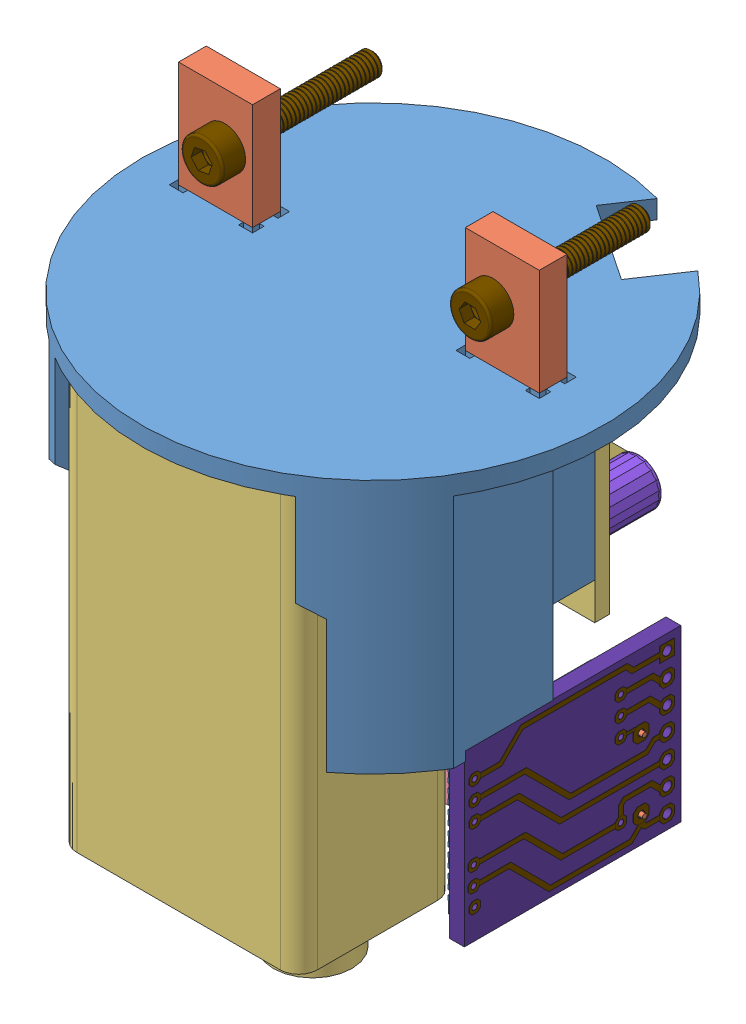
SolidWorks assembly Elektro, configuration Standard. Lengths in mm.
Overall size (50 63.5 50).
67 component instances, 62 part files, 22 mates.
Components (placement in the parent):
- E-Part-1: E-Part [Standard] at (0.3501 -2.1253 50) size (50 27.5 50)
- E-Befestigung-1: E-Befestigung [Standard] at (-12.1499 -0.1253 50.5) size (8 11.5 3)
- E-Befestigung-2: E-Befestigung [Standard] at (10.8501 -0.1253 47.5) x (-1 0 0) z (0 0 -1) size (8 11.5 3)
- 9V-1: 9V [Standard] at (-12.6499 -2.1253 54) x (0 0 -1) z (-1 0 0) size (17 50 26)
- Zeitschaltung-1: Zeitschaltung [Standard] at (0.3501 -30.1253 48.2) x (0 1 0) z (0 0 -1) size (30 30 20.34)
  - Zeitschaltung_Board-1: Zeitschaltung_Board [Standard] at origin size (30 30 1.6)
  - Zeitschaltung_PadsAndTracks-1: Zeitschaltung_PadsAndTracks [Standard] at origin size (28.67 28.55 1.67)
  - Zeitschaltung_K1-1: Zeitschaltung_K1 [Standard] at origin size (2.54 5.08 10.74) (hidden)
  - Zeitschaltung_K2-1: Zeitschaltung_K2 [Standard] at origin size (7.62 2.54 10.74) (hidden)
  - Zeitschaltung_K3-1: Zeitschaltung_K3 [Standard] at origin size (7.62 2.54 10.74) (hidden)
  - Zeitschaltung_K4-1: Zeitschaltung_K4 [Standard] at origin size (5.08 7.62 10.74)
  - Zeitschaltung_K6-1: Zeitschaltung_K6 [Standard] at origin size (2.54 5.08 10.74) (hidden)
  - Zeitschaltung_IC3-1: Zeitschaltung_IC3 [Standard] at origin size (8.8 8.8 1.61)
  - Zeitschaltung_D5-1: Zeitschaltung_D5 [Standard] at origin size (3.7 3 2.09)
  - Zeitschaltung_R1-1: Zeitschaltung_R1 [Standard] at origin size (3.2 1.6 0.61)
  - Zeitschaltung_R5-1: Zeitschaltung_R5 [Standard] at origin size (3.2 1.6 0.61)
  - Zeitschaltung_K5-1: Zeitschaltung_K5 [Standard] at origin size (17.78 2.54 12) (hidden)
  - Zeitschaltung_R4-1: Zeitschaltung_R4 [Standard] at origin size (3.2 1.6 0.61)
  - Zeitschaltung_X2-1: Zeitschaltung_X2 [Standard] at origin size (5 6.04 1.86)
  - Zeitschaltung_C2-1: Zeitschaltung_C2 [Standard] at origin size (3.2 1.6 0.61)
  - Zeitschaltung_R2-1: Zeitschaltung_R2 [Standard] at origin size (4.7 6.5 7)
  - Zeitschaltung_T1-1: Zeitschaltung_T1 [Standard] at origin size (10.42 6.5 2.38)
  - Zeitschaltung_K7-1: Zeitschaltung_K7 [Standard] at origin size (2.54 5.08 12) (hidden)
  - Zeitschaltung_T2-1: Zeitschaltung_T2 [Standard] at origin size (3 2.6 1.1)
- Funkchip-1: Funkchip [Standard] at (20.9501 -26.6253 38.1) x (0 -1 0) z (-1 0 0) size (18.4 23.4 12)
  - Funkchip_Board-1: Funkchip_Board [Standard] at origin size (18.4 23.4 1.6)
  - Funkchip_PadsAndTracks-1: Funkchip_PadsAndTracks [Standard] at origin size (17.1 22.3 1.67)
  - Funkchip_IC1-1: Funkchip_IC1 [Standard] at origin size (16.1 15.9 4.2)
  - Funkchip_R1-1: Funkchip_R1 [Standard] at origin size (8.15 1.8 3.85)
  - Funkchip_K1-1: Funkchip_K1 [Standard] at origin size (17.78 2.54 12) (hidden)
- Bewegungsmelder-1: Bewegungsmelder [Standard] at (-14.6499 -2.1253 42.2) x (1 0 0) z (0 0 -1) size (32 24.8 16.02)
  - Bewegungsmelder_Board-1: Bewegungsmelder_Board [Standard] at origin size (32 24 1.6)
  - Bewegungsmelder_PadsAndTracks-1: Bewegungsmelder_PadsAndTracks [Standard] at origin size (30.89 22.22 1.67)
  - Bewegungsmelder_K1-1: Bewegungsmelder_K1 [Standard] at origin size (7.62 2.54 12) (hidden)
  - Bewegungsmelder_GEH1-1: Bewegungsmelder_GEH1 [Standard] at origin size (5 5 13.11)
  - Bewegungsmelder_GEH2-1: Bewegungsmelder_GEH2 [Standard] at origin size (5 5 13.11)
  - Bewegungsmelder_GEH3-1: Bewegungsmelder_GEH3 [Standard] at origin size (5 5 13.11)
  - Bewegungsmelder_GEH4-1: Bewegungsmelder_GEH4 [Standard] at origin size (5 5 13.11)
  - Bewegungsmelder_GEH5-1: Bewegungsmelder_GEH5 [Standard] at origin size (6.2 9.9 1.76)
  - Bewegungsmelder_T2-1: Bewegungsmelder_T2 [Standard] at origin size (5 4.05 1.65)
  - Bewegungsmelder_R1-1: Bewegungsmelder_R1 [Standard] at origin size (9.8 5.2 16.02)
  - Bewegungsmelder_R2-1: Bewegungsmelder_R2 [Standard] at origin size (9.8 5.2 16.02)
  - Bewegungsmelder_D1-1: Bewegungsmelder_D1 [Standard] at origin size (3.5 1.5 1.5)
  - Bewegungsmelder_GEH6-1: Bewegungsmelder_GEH6 [Standard] at origin size (1.7 0.95 0.55)
  - Bewegungsmelder_GEH7-1: Bewegungsmelder_GEH7 [Standard] at origin size (1.7 0.95 0.55)
  - Bewegungsmelder_GEH8-1: Bewegungsmelder_GEH8 [Standard] at origin size (1.7 0.95 0.55)
  - Bewegungsmelder_GEH9-1: Bewegungsmelder_GEH9 [Standard] at origin size (1.7 0.95 0.55)
  - Bewegungsmelder_GEH10-1: Bewegungsmelder_GEH10 [Standard] at origin size (1.7 0.95 0.55)
  - Bewegungsmelder_GEH11-1: Bewegungsmelder_GEH11 [Standard] at origin size (1.7 0.95 0.55)
  - Bewegungsmelder_GEH12-1: Bewegungsmelder_GEH12 [Standard] at origin size (1.7 0.95 0.55)
  - Bewegungsmelder_GEH13-1: Bewegungsmelder_GEH13 [Standard] at origin size (1.7 0.95 0.55)
  - Bewegungsmelder_GEH14-1: Bewegungsmelder_GEH14 [Standard] at origin size (1.7 0.95 0.55)
  - Bewegungsmelder_GEH15-1: Bewegungsmelder_GEH15 [Standard] at origin size (1.7 0.95 0.55)
  - Bewegungsmelder_GEH16-1: Bewegungsmelder_GEH16 [Standard] at origin size (1.7 0.95 0.55)
  - Bewegungsmelder_GEH17-1: Bewegungsmelder_GEH17 [Standard] at origin size (1.7 0.95 0.55)
  - Bewegungsmelder_GEH18-1: Bewegungsmelder_GEH18 [Standard] at origin size (1.7 0.95 0.55)
  - Bewegungsmelder_GEH19-1: Bewegungsmelder_GEH19 [Standard] at origin size (1.7 0.95 0.55)
  - Bewegungsmelder_GEH20-1: Bewegungsmelder_GEH20 [Standard] at origin size (1.7 0.95 0.55)
  - Bewegungsmelder_GEH21-1: Bewegungsmelder_GEH21 [Standard] at origin size (1.7 0.95 0.55)
  - Bewegungsmelder_GEH22-1: Bewegungsmelder_GEH22 [Standard] at origin size (1.7 0.95 0.55)
  - Bewegungsmelder_GEH23-1: Bewegungsmelder_GEH23 [Standard] at origin size (1.7 0.95 0.55)
  - Bewegungsmelder_GEH24-1: Bewegungsmelder_GEH24 [Standard] at origin size (1.7 0.95 0.55)
  - Bewegungsmelder_GEH25-1: Bewegungsmelder_GEH25 [Standard] at origin size (1.7 0.95 0.55)
  - Bewegungsmelder_GEH26-1: Bewegungsmelder_GEH26 [Standard] at origin size (1.7 0.95 0.55)
  - Bewegungsmelder_GEH27-1: Bewegungsmelder_GEH27 [Standard] at origin size (0.95 1.7 0.55)
- socket head cap screw 4762_din-1: socket head cap screw 4762_din [ISO 4762 M2.5 x 16 --- 16S] at (-15.1499 5.8747 53) x (0 0 -1) z (0.192877 -0.981223 0) size (18.5 4.5 4.5)
- socket head cap screw 4762_din-2: socket head cap screw 4762_din [ISO 4762 M2.5 x 16 --- 16S] at (13.8501 5.8747 53) x (0 0 -1) z (-0.883445 -0.468535 0) size (18.5 4.5 4.5)
Mates (geometry in assembly coordinates):
- Deckungsgleich5: coincident anti-aligned: plane of E-Part-1 through (0.3501 -0.1253 50) normal (0 1 0); plane of E-Befestigung-1 through (-12.1499 -0.1253 50.5) normal (0 -1 0)
- Deckungsgleich6: coincident anti-aligned: plane of E-Part-1 through (0.3501 -0.1253 50) normal (0 1 0); plane of E-Befestigung-2 through (10.8501 -0.1253 47.5) normal (0 -1 0)
- Deckungsgleich14: coincident anti-aligned: plane of E-Part-1 through (0.3501 -2.1253 50) normal (0 -1 0); plane of 9V-1 through (-12.6499 -2.1253 54) normal (0 1 0)
- Deckungsgleich20: coincident anti-aligned: plane of E-Part-1 through (-12.6499 -27.1253 54) normal (1 0 0); plane of 9V-1 through (-12.6499 -52.1253 54) normal (-1 0 0)
- Deckungsgleich21: coincident anti-aligned: plane of E-Part-1 through (13.3501 -27.1253 54) normal (0 0 1); plane of 9V-1 through (-12.6499 -52.1253 54) normal (0 0 -1)
- Deckungsgleich33: coincident aligned: plane of E-Part-1 through (-20.1499 -0.1253 50) normal (-1 0 0); plane of E-Befestigung-1 through (-20.1499 11.3747 50.5) normal (-1 0 0)
- Deckungsgleich34: coincident aligned: plane of E-Part-1 through (0.3501 -0.1253 50.5) normal (0 0 1); plane of E-Befestigung-1 through (-12.1499 11.3747 50.5) normal (0 0 1)
- Deckungsgleich35: coincident aligned: plane of E-Part-1 through (0.3501 -0.1253 50.5) normal (0 0 1); plane of E-Befestigung-2 through (10.8501 11.3747 50.5) normal (0 0 1)
- Deckungsgleich36: coincident aligned: plane of E-Part-1 through (18.8501 -0.1253 50) normal (1 0 0); plane of E-Befestigung-2 through (18.8501 11.3747 47.5) normal (1 0 0)
- Deckungsgleich40: coincident anti-aligned: plane of E-Part-1 through (0.3501 -2.1253 50) normal (0 -1 0); plane of Bewegungsmelder-1/Bewegungsmelder_Board-1 through (-14.6499 -2.1253 43) normal (0 1 0)
- Deckungsgleich41: coincident anti-aligned: plane of E-Part-1 through (-14.6499 -22.1253 40) normal (1 0 0); plane of Bewegungsmelder-1/Bewegungsmelder_Board-1 through (-14.6499 -26.1253 43) normal (-1 0 0)
- Deckungsgleich42: coincident anti-aligned: plane of E-Part-1 through (15.3501 -22.1253 43) normal (0 0 -1); plane of Bewegungsmelder-1/Bewegungsmelder_Board-1 through (-14.6499 -26.1253 43) normal (0 0 1)
- Deckungsgleich43: coincident anti-aligned: plane of E-Part-1 through (-14.6499 -22.1253 40) normal (1 0 0); plane of Zeitschaltung-1/Zeitschaltung_Board-1 through (-14.6499 -45.1253 49) normal (-1 0 0)
- Deckungsgleich44: coincident anti-aligned: plane of E-Part-1 through (8.3501 -15.1253 49) normal (0 0 -1); plane of Zeitschaltung-1/Zeitschaltung_Board-1 through (15.3501 -45.1253 49) normal (0 0 1)
- Deckungsgleich45: coincident anti-aligned: plane of E-Part-1 through (0.3501 -15.1253 50) normal (0 -1 0); plane of Zeitschaltung-1/Zeitschaltung_Board-1 through (-14.6499 -15.1253 49) normal (0 1 0)
- Deckungsgleich47: coincident anti-aligned: plane of E-Part-1 through (21.8501 -26.6253 61.5) normal (0 0 -1); plane of Funkchip-1/Funkchip_Board-1 through (21.7501 -45.0253 61.5) normal (0 0 1)
- Deckungsgleich48: coincident anti-aligned: plane of E-Part-1 through (0.3501 -26.6253 50) normal (0 -1 0); plane of Funkchip-1/Funkchip_Board-1 through (21.7501 -26.6253 61.5) normal (0 1 0)
- Deckungsgleich49: coincident anti-aligned: plane of E-Part-1 through (20.1501 -26.6253 52) normal (1 0 0); plane of Funkchip-1/Funkchip_Board-1 through (20.1501 -26.6253 61.5) normal (-1 0 0)
- Konzentrisch34: concentric anti-aligned: cylinder of E-Befestigung-1 through (-15.1499 5.8747 57.5) axis (0 0 -1) radius 1.25; cylinder of socket head cap screw 4762_din-1 through (-15.1499 5.8747 84.75) axis (0 0 1) radius 1.25
- Deckungsgleich50: coincident anti-aligned: plane of E-Befestigung-1 through (-12.1499 11.3747 50.5) normal (0 0 1); plane of socket head cap screw 4762_din-1 through (-12.9422 6.3087 50.5) normal (0 0 -1)
- Deckungsgleich51: coincident anti-aligned: plane of E-Befestigung-2 through (10.8501 11.3747 50.5) normal (0 0 1); plane of socket head cap screw 4762_din-2 through (14.9043 3.887 50.5) normal (0 0 -1)
- Konzentrisch35: concentric aligned: cylinder of E-Befestigung-2 through (13.8501 5.8747 40.5) axis (0 0 1) radius 1.25; cylinder of socket head cap screw 4762_din-2 through (13.8501 5.8747 84.75) axis (0 0 1) radius 1.25
